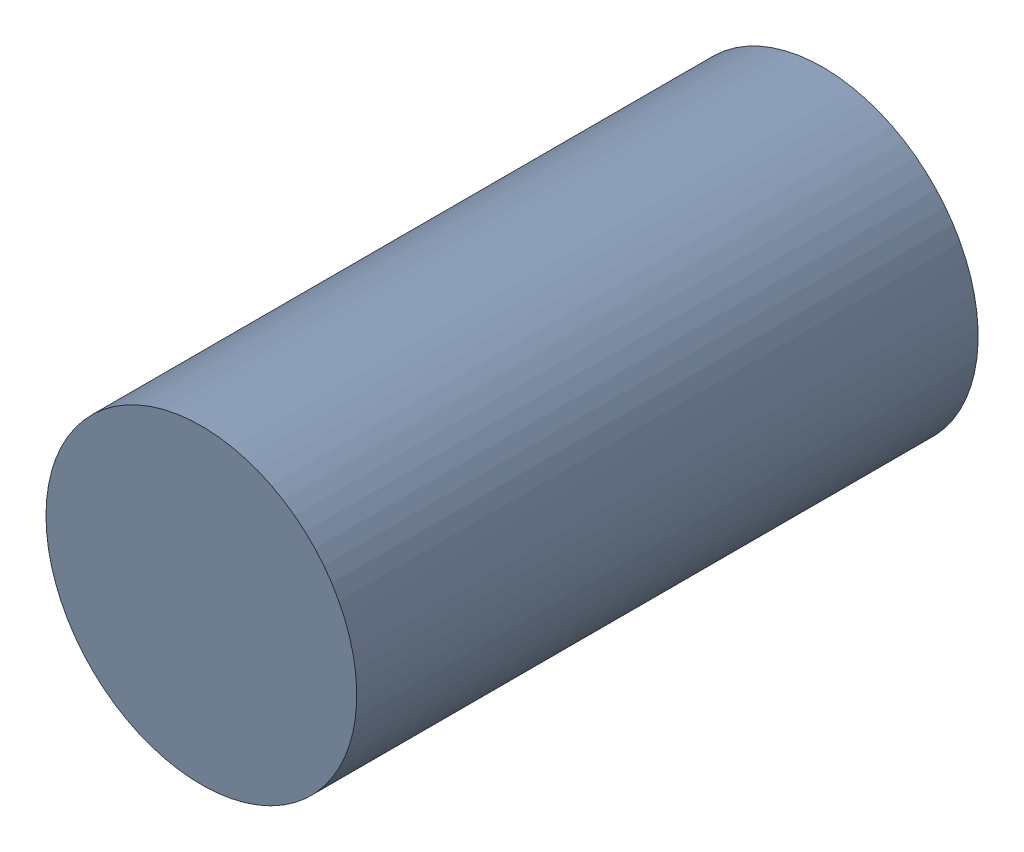
SolidWorks assembly MH7, configuration Default. Lengths in mm.
Overall size (1 1 2).
2 component instances, 1 part files, 0 mates.
Components (placement in the parent):
- 11929539264-1: 11929539264 [Default] at (146.3363 110.9276 -1.5) x (-1 0 0) z (0 0 1) size (1 1 2)
  - Cylinder-1: Cylinder [Default] at origin size (1 1 2)
